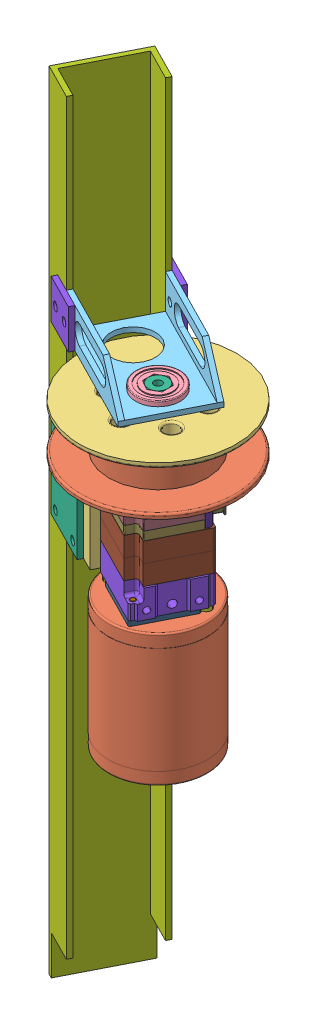
SolidWorks assembly Spool_Assem, configuration Default. Lengths in mm.
35 component instances, 26 part files, 38 mates.
Components (placement in the parent):
- Hub-1: Hub [Default] at origin size (55.88 12.7 55.88)
- Spool_Outside-1: Spool_Outside [Default] x (1 0 0) z (0 -1 0) size (101.6 101.6 15.88)
- Spool_Inside-1: Spool_Inside [Default] at origin size (101.6 15.88 101.6)
- VersaPlanetary_v2_Two_Stage_with_Encoder-1: VersaPlanetary_v2_Two_Stage_with_Encoder [Default] at (20.2874 -65.8645 56.4601) x (0 1 0) z (-0.45319 0 0.891414) size (121.79 44.49 58.8)
  - 217-2625-026 Rev1-1: 217-2625-026 Rev1 [Default] at (25.4052 43.6717 -41.1353) x (0 -1 0) z (-1 0 0) size (44.45 42 18.13)
  - 217-2742-001 Rev4-1: 217-2742-001 Rev4 [Default] at (30.4052 43.6717 -41.1353) x (1 0 0) z (0 -0.092627 0.995701) size (7 28 28)
  - 217-2742-001 Rev4-2: 217-2742-001 Rev4 [Default] at (41.5302 43.6717 -41.1353) size (7 28 28)
  - 217-2625-003 Rev1-1: 217-2625-003 Rev1 [Default] at (40.7778 43.6717 -41.1353) x (0 -0.891414 -0.45319) z (1 0 0) size (17 17 64.12)
  - 832-2250-Base-Kit-Screw_SSA0832-0500ZC-1: 832-2250-Base-Kit-Screw_SSA0832-0500ZC [Default] at (-24.1948 26.1717 -58.6353) x (0 -0.767799 -0.640691) z (0 0.640691 -0.767799) size (6.73 61.21 6.73)
  - 832-2250-Base-Kit-Screw_SSA0832-0500ZC-2: 832-2250-Base-Kit-Screw_SSA0832-0500ZC [Default] at (-24.1948 61.1717 -23.6353) x (0 0.961307 0.275478) z (0 -0.275478 0.961307) size (6.73 61.21 6.73)
  - 217-2625-025 Rev1-1: 217-2625-025 Rev1 [Default] at (-16.6948 43.6717 -41.1353) x (0 -1 0) z (-1 0 0) size (44.45 42 18)
  - 217-4649-002 Rev1_SSA0832-0500ZC-1: 217-4649-002 Rev1_SSA0832-0500ZC [Default] at (-27.1948 25.7111 -23.1748) x (0 0.33842 -0.940995) z (0 0.940995 0.33842) size (6.73 16.76 6.73)
  - 217-4649-002 Rev1_SSA0832-0500ZC-2: 217-4649-002 Rev1_SSA0832-0500ZC [Default] at (-27.1948 61.6322 -59.0958) x (0 -0.308932 -0.951084) z (0 0.951084 -0.308932) size (6.73 16.76 6.73)
  - 217-2822-003 Rev4-1: 217-2822-003 Rev4 [Default] at (-25.6948 43.6717 -41.1353) x (0 -1 0) z (-1 0 0) size (42 42 4.8)
  - 217-2816-001 Rev1-1: 217-2816-001 Rev1 [Default] at (12.8552 43.6717 -41.1353) x (0 -1 0) z (1 0 0) size (42 42 14.5)
  - 217-2816-001 Rev1-2: 217-2816-001 Rev1 [Default] at (0.1552 43.6717 -41.1353) x (0 -1 0) z (1 0 0) size (42 42 14.5)
  - VersaPlanetary_Integrated_Encoder_217-5046-1: VersaPlanetary_Integrated_Encoder_217-5046 [Default] at (24.7052 43.6717 -41.1353) x (0 0 1) z (-1 0 0) size (58.06 43.13 18.16)
    - 217-4783-001 Rev3-1: 217-4783-001 Rev3 [Default] at (0 0 2.75) size (53.55 42 11.11)
    - 217-4783-002 Rev7_Sealed Config-1: 217-4783-002 Rev7_Sealed Config [Default] at (0 0 -7.2) x (0 1 0) z (0 0 1) size (42 51.56 9.32)
    - 217-4783-008 Rev2-1: 217-4783-008 Rev2 [Default] at (-20.05 0 2.2) x (0.307149 -0.951661 0) z (0.951661 0.307149 0) size (5 4 5)
    - PCBA Rev3-1: PCBA Rev3 [Default] at (-20.05 0 -2.1252) x (0 1 0) z (-1 0 0) size (15.93 10.15 24.44)
    - 217-2788-001 Rev3_57155K375-1: 217-2788-001 Rev3_57155K375 [Default] at (-20.05 0 3.8125) x (-0.99574 0.092202 0) z (0 0 1) size (9.53 9.53 3.17)
    - 217-4783-006 Rev3-1: 217-4783-006 Rev3 [Default] at (17.5 17.5 -0.85) x (-0.867641 0.497191 0) z (0 0 1) size (5.9 5.9 12.7)
    - 217-4783-006 Rev3-2: 217-4783-006 Rev3 [Default] at (-17.5 -17.5 -0.85) x (0.825154 -0.564908 0) z (0 0 1) size (5.9 5.9 12.7)
    - 217-4783-007 Rev1-1: 217-4783-007 Rev1 [Default] at (-16.45 0 -5.2) x (0 1 0) z (0 0 1) size (6 10.71 3.56)
    - 217-4783-003 Rev4-1: 217-4783-003 Rev4 [Default] at (-20.05 0 -1.02) x (0 1 0) z (0 0 1) size (23.4 21.71 4.21)
- MiniCIM Motor-1: MiniCIM Motor [Default] at (0 -93.0593 0) x (0 -1 0) z (0.950779 0 -0.309871) size (125.82 64.01 64.01)
- Spool_Gearbox_Mount-1: Spool_Gearbox_Mount [Default] at (-31.3227 -89.2568 12.5698) x (0.45319 0 -0.891414) z (0 1 0) size (50.8 25.4 71.12)
- Hex_Bearing-1: Hex_Bearing [Default] at (0 24.6657 0) x (-0.898928 0 0.438096) z (0 -1 0) size (31.12 31.12 7.93)
- Spool_Bearing_Mount-1: Spool_Bearing_Mount [Default] at (28.4925 18.2624 -14.0086) x (-0.45319 0 0.891414) z (-0.891414 0 -0.45319) size (50.8 25.4 76.2)
- Spool_Plate2-1: Spool_Plate2 [Default] at (-15.3525 -89.2568 -39.8609) x (0 1 0) z (-0.45319 0 0.891414) size (71.12 38.1 3.17)
- Spool_Frame_Support-2: Spool_Frame_Support [Default] at (-85.0972 152.0545 -14.7689) x (0.45319 0 -0.891414) z (0 -1 0) size (50.8 25.4 508)
- Spool_Plate3-1: Spool_Plate3 [Default] at (-49.3154 43.6624 -57.1275) x (0 -1 0) z (-0.45319 0 0.891414) size (25.4 25.4 3.17)
- Spool_Plate3-2: Spool_Plate3 [Default] at (-73.7763 43.6624 -9.0134) x (0 -1 0) z (-0.45319 0 0.891414) size (25.4 25.4 3.17)
- Spool_Plate2-2: Spool_Plate2 [Default] at (-39.8134 -89.2568 8.2531) x (0 1 0) z (-0.45319 0 0.891414) size (71.12 38.1 3.17)
Mates (geometry in assembly coordinates):
- Coincident1: coincident anti-aligned: plane of Hub-1 through (0 0 0) normal (0 -1 0); plane of Spool_Outside-1 through (0 0 0) normal (0 1 0)
- Concentric1: concentric anti-aligned: cylinder of Hub-1 through (0 12.7 0) axis (0 -1 0) radius 14.2875; cylinder of Spool_Outside-1 through (0 -12.7 0) axis (0 1 0) radius 31.75
- Concentric2: concentric aligned: circle of Hub-1; circle of Spool_Outside-1
- Coincident2: coincident anti-aligned: plane of Spool_Outside-1 through (0 0 0) normal (0 1 0); plane of Spool_Inside-1 through (0 0 0) normal (0 -1 0)
- Coincident6: coincident anti-aligned: circle of Spool_Outside-1; circle of Spool_Inside-1
- Concentric6: concentric anti-aligned: circle of Spool_Outside-1; circle of Spool_Inside-1
- Concentric7: concentric anti-aligned: circle of Spool_Outside-1; circle of Spool_Inside-1
- Concentric8: concentric anti-aligned: circle of VersaPlanetary_v2_Two_Stage_with_Encoder-1/217-2822-003 Rev4-1; circle of MiniCIM Motor-1
- Concentric9: concentric anti-aligned: circle of VersaPlanetary_v2_Two_Stage_with_Encoder-1/217-2625-025 Rev1-1; circle of MiniCIM Motor-1
- Coincident7: coincident anti-aligned: plane of VersaPlanetary_v2_Two_Stage_with_Encoder-1/217-2822-003 Rev4-1 through (0 -93.0593 0) normal (0 -1 0); plane of MiniCIM Motor-1 through (0 -93.0593 0) normal (0 1 0)
- Concentric11: concentric anti-aligned: circle of Spool_Inside-1; circle of VersaPlanetary_v2_Two_Stage_with_Encoder-1/217-2625-026 Rev1-1
- Coincident8: coincident anti-aligned: plane of VersaPlanetary_v2_Two_Stage_with_Encoder-1/217-2625-026 Rev1-1 through (-9.7395 -17.3343 -29.8838) normal (-0.891414 0 -0.45319); plane of Spool_Gearbox_Mount-1 through (-31.3227 -18.1368 12.5698) normal (0.891414 0 0.45319)
- Parallel3: parallel: line of Hub-1 through (0 12.7 -7.3323) axis (-0.866025 0 0.5); plane of VersaPlanetary_v2_Two_Stage_with_Encoder-1/217-2625-003 Rev1-1 through (0 24.6657 -7.3323) normal (-0.5 0 -0.866025)
- Coincident10: coincident anti-aligned: plane of VersaPlanetary_v2_Two_Stage_with_Encoder-1/217-2625-026 Rev1-1 through (-9.7395 -17.3343 -29.8838) normal (-0.891414 0 -0.45319); plane of Spool_Gearbox_Mount-1 through (-31.3227 -18.1368 12.5698) normal (0.891414 0 0.45319)
- Width1: width anti-aligned: plane of Spool_Gearbox_Mount-1 through (-8.3006 -18.1368 -32.7141) normal (0.45319 0 -0.891414); plane of Spool_Gearbox_Mount-1 through (-31.3227 -18.1368 12.5698) normal (-0.45319 0 0.891414); plane of VersaPlanetary_v2_Two_Stage_with_Encoder-1/217-2625-026 Rev1-1 through (9.2027 -35.4593 28.2367) normal (-0.45319 0 0.891414); plane of VersaPlanetary_v2_Two_Stage_with_Encoder-1/217-2625-026 Rev1-1 through (28.2367 -35.4593 -9.2027) normal (0.45319 0 -0.891414)
- Concentric13: concentric anti-aligned: circle of Spool_Inside-1; circle of Hex_Bearing-1
- Parallel4: parallel: plane of VersaPlanetary_v2_Two_Stage_with_Encoder-1/217-2625-003 Rev1-1 through (6.35 24.6657 3.6662) normal (1 0 0); line of Hex_Bearing-1 through (-6.35 16.7384 -3.6662) axis (0 0 1)
- Concentric14: concentric anti-aligned: circle of Hex_Bearing-1; circle of Spool_Bearing_Mount-1
- Coincident13: coincident anti-aligned: plane of Hex_Bearing-1 through (-12.558 18.2624 6.1202) normal (0 1 0); plane of Spool_Bearing_Mount-1 through (-39.4333 18.2624 -48.5417) normal (0 -1 0)
- Coincident14: coincident aligned: plane of Spool_Gearbox_Mount-1 through (-8.3006 -18.1368 -32.7141) normal (0.45319 0 -0.891414); plane of Spool_Bearing_Mount-1 through (-39.4333 18.2624 -48.5417) normal (0.45319 0 -0.891414)
- Coincident17: coincident aligned: plane of VersaPlanetary_v2_Two_Stage_with_Encoder-1/217-2625-003 Rev1-1 through (-6.35 24.6657 3.6662) normal (0 1 0); plane of Hex_Bearing-1 through (0 24.6657 0) normal (0 1 0)
- Coincident18: coincident anti-aligned: plane of Spool_Gearbox_Mount-1 through (-8.3006 -18.1368 -32.7141) normal (0.45319 0 -0.891414); plane of Spool_Plate2-1 through (-16.7914 -89.2568 -37.0307) normal (-0.45319 0 0.891414)
- Parallel5: parallel anti-aligned: line of Spool_Gearbox_Mount-1 through (-30.9426 -18.1368 -44.2251) axis (0 -1 0); line of Spool_Plate2-1 through (-15.3525 -89.2568 -39.8609) axis (0 1 0)
- Coincident19: coincident aligned: plane of Spool_Gearbox_Mount-1 through (-31.3227 -89.2568 12.5698) normal (0 -1 0); plane of Spool_Plate2-1 through (-16.7914 -89.2568 -37.0307) normal (0 -1 0)
- Coincident23: coincident anti-aligned: plane of Spool_Bearing_Mount-1 through (-39.4333 18.2624 -48.5417) normal (-0.891414 0 -0.45319); plane of Spool_Frame_Support-2 through (-39.4333 -355.9455 -48.5417) normal (0.891414 0 0.45319)
- Coincident24: coincident aligned: plane of Spool_Bearing_Mount-1 through (-39.4333 18.2624 -48.5417) normal (0.45319 0 -0.891414); plane of Spool_Frame_Support-2 through (-62.0752 -355.9455 -60.0528) normal (0.45319 0 -0.891414)
- Width2: width aligned: plane of VersaPlanetary_v2_Two_Stage_with_Encoder-1/217-2625-025 Rev1-1 through (9.7395 -90.0593 29.8838) normal (0 -1 0); plane of VersaPlanetary_v2_Two_Stage_with_Encoder-1/217-2625-026 Rev1-1 through (-29.8838 -17.3343 9.7395) normal (0 1 0); plane of Spool_Gearbox_Mount-1 through (-31.3227 -89.2568 12.5698) normal (0 -1 0); plane of Spool_Gearbox_Mount-1 through (-31.3227 -18.1368 12.5698) normal (0 1 0)
- Distance2: distance = 12.7 mm: line of Spool_Plate2-1 through (-49.3154 -18.1368 -57.1275) axis (0 -1 0); plane of Spool_Frame_Support-2 through (-85.0972 -355.9455 -14.7689) normal (-0.891414 0 -0.45319)
- Coincident25: coincident anti-aligned: plane of Spool_Frame_Support-2 through (-62.0752 -355.9455 -60.0528) normal (0.45319 0 -0.891414); plane of Spool_Plate3-1 through (-50.7542 43.6624 -54.2972) normal (-0.45319 0 0.891414)
- Parallel6: parallel anti-aligned: line of Spool_Frame_Support-2 through (-62.0752 -355.9455 -60.0528) axis (0 1 0); line of Spool_Plate3-1 through (-49.3154 43.6624 -57.1275) axis (0 -1 0)
- Coincident26: coincident aligned: plane of Spool_Plate2-1 through (-50.7542 -89.2568 -54.2972) normal (-0.891414 0 -0.45319); plane of Spool_Plate3-1 through (-50.7542 43.6624 -54.2972) normal (-0.891414 0 -0.45319)
- Coincident27: coincident aligned: plane of Spool_Bearing_Mount-1 through (-39.4333 18.2624 -48.5417) normal (0 -1 0); plane of Spool_Plate3-1 through (-50.7542 18.2624 -54.2972) normal (0 -1 0)
- Coincident28: coincident anti-aligned: plane of Spool_Frame_Support-2 through (-85.0972 -355.9455 -14.7689) normal (-0.45319 0 0.891414); plane of Spool_Plate3-2 through (-73.7763 43.6624 -9.0134) normal (0.45319 0 -0.891414)
- Coincident29: coincident aligned: plane of Spool_Plate3-1 through (-50.7542 43.6624 -54.2972) normal (0 1 0); plane of Spool_Plate3-2 through (-75.2152 43.6624 -6.1832) normal (0 1 0)
- Coincident30: coincident aligned: plane of Spool_Plate3-1 through (-28.1123 43.6624 -42.7862) normal (0.891414 0 0.45319); plane of Spool_Plate3-2 through (-52.5733 43.6624 5.3279) normal (0.891414 0 0.45319)
- Coincident31: coincident anti-aligned: plane of Spool_Gearbox_Mount-1 through (-31.3227 -18.1368 12.5698) normal (-0.45319 0 0.891414); plane of Spool_Plate2-2 through (-39.8134 -89.2568 8.2531) normal (0.45319 0 -0.891414)
- Coincident32: coincident aligned: plane of Spool_Gearbox_Mount-1 through (-31.3227 -89.2568 12.5698) normal (0 -1 0); plane of Spool_Plate2-2 through (-41.2523 -89.2568 11.0834) normal (0 -1 0)
- Coincident33: coincident aligned: plane of Spool_Plate2-1 through (-16.7914 -89.2568 -37.0307) normal (0.891414 0 0.45319); plane of Spool_Plate2-2 through (-41.2523 -89.2568 11.0834) normal (0.891414 0 0.45319)
